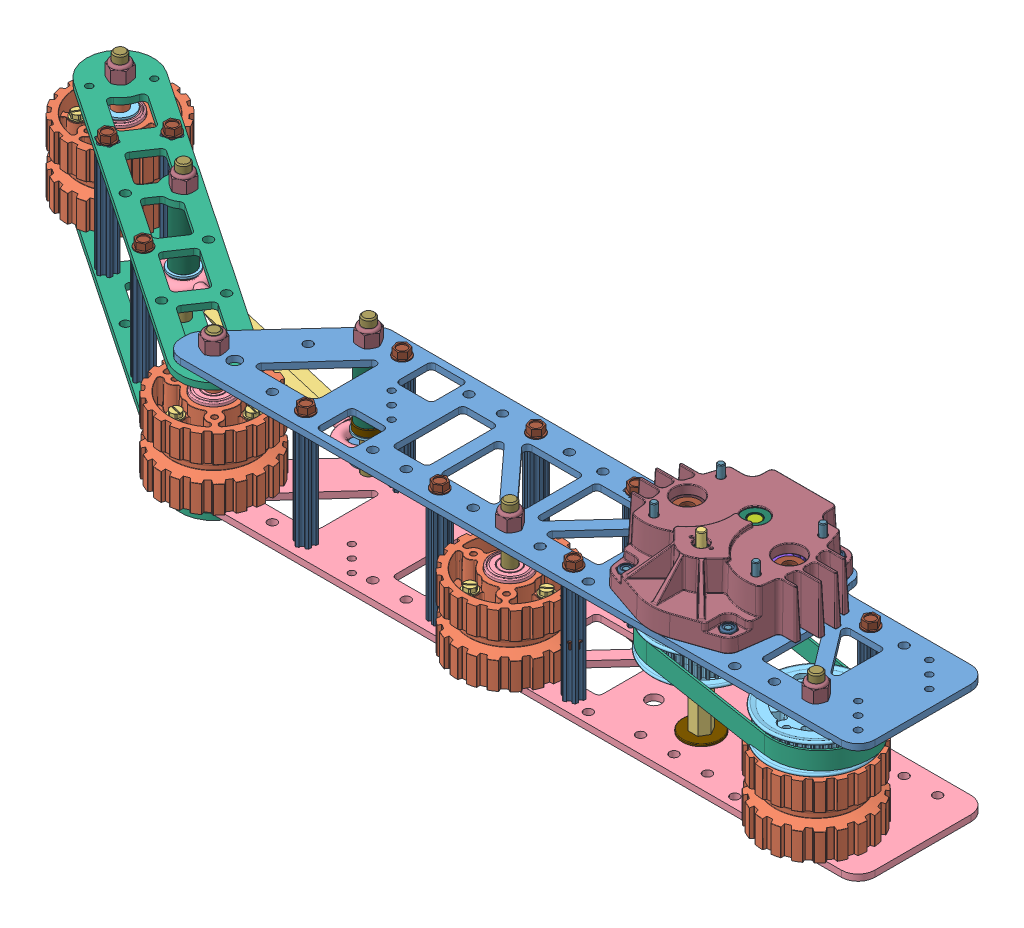
SolidWorks assembly TankDriveRightSide, configuration Default. Lengths in mm.
Overall size (781.55 148.41 261.62).
162 component instances, 41 part files, 0 mates.
Components (placement in the parent):
- am-3319 Inside Plate-1: am-3319 Inside Plate [Default] at (-236.8957 -8.1516 48.6059) size (527.05 4.76 117.47)
- 20T pulley back to back-1: 20T pulley back to back [Default] at (-148.1587 -69.0627 26.6681) x (0.970425 0 0.241402) z (-0.241402 0 0.970425) size (79.28 58.42 79.28)
  - am-3298 20 tooth Molded Tank Pulley Half r3-1: am-3298 20 tooth Molded Tank Pulley Half r3 [Default] at (-66.929 10.7589 19.6249) size (79.28 27.95 79.28)
  - am-3298 20 tooth Molded Tank Pulley Half r3-2: am-3298 20 tooth Molded Tank Pulley Half r3 [Default] at (-66.929 10.7589 19.6249) x (1 0 0) z (0 0 -1) size (79.28 27.95 79.28)
  - 10-24 Hex Washer Rolling x 1.25_93882A213-1: 10-24 Hex Washer Rolling x 1.25_93882A213 [Default] at (-46.3067 30.1899 7.7187) x (1 0 0) z (0 1 0) size (10.52 10.52 35.59)
  - 10-24 Hex Washer Rolling x 1.25_93882A213-2: 10-24 Hex Washer Rolling x 1.25_93882A213 [Default] at (-87.5512 30.1899 7.7187) x (1 0 0) z (0 1 0) size (10.52 10.52 35.59)
  - 10-24 Hex Washer Rolling x 1.25_93882A213-3: 10-24 Hex Washer Rolling x 1.25_93882A213 [Default] at (-66.929 30.1899 43.4374) x (1 0 0) z (0 1 0) size (10.52 10.52 35.59)
  - 10-24 Hex Washer Rolling x 1.25_93882A213-4: 10-24 Hex Washer Rolling x 1.25_93882A213 [Default] at (-66.929 -8.6721 -4.1876) x (-0.837169 0 -0.546944) z (0 -1 0) size (10.52 10.52 35.59)
  - 10-24 Hex Washer Rolling x 1.25_93882A213-5: 10-24 Hex Washer Rolling x 1.25_93882A213 [Default] at (-87.5512 -8.6721 31.5312) x (-0.837169 0 -0.546944) z (0 -1 0) size (10.52 10.52 35.59)
  - 10-24 Hex Washer Rolling x 1.25_93882A213-6: 10-24 Hex Washer Rolling x 1.25_93882A213 [Default] at (-46.3067 -8.6721 31.5312) x (-0.837169 0 -0.546944) z (0 -1 0) size (10.52 10.52 35.59)
  - 1614Z Bearing-1: 1614Z Bearing [Default] at (-66.929 -13.6886 19.6249) x (1 0 0) z (0 1 0) size (28.58 28.58 9.53)
  - 1614Z Bearing-2: 1614Z Bearing [Default] at (-66.929 35.2064 19.6249) x (1 0 0) z (0 -1 0) size (28.58 28.58 9.53)
- am-1393 375 washer-1: am-1393 375 washer [Default] at (-217.8457 -89.1141 29.5567) x (-0.876798 0 0.480859) z (-0.480859 0 -0.876798) size (20.62 1.6 20.62)
- am-3320 Upper Bar-1: am-3320 Upper Bar [Default] at (-436.3184 -98.6391 -117.8038) x (0.82904 0 0.55919) z (-0.55919 0 0.82904) size (314.32 4.76 50.8)
- am-3320 Upper Bar-2: am-3320 Upper Bar [Default] at (-436.3184 -12.9141 -117.8038) x (0.82904 0 0.55919) z (-0.55919 0 0.82904) size (314.32 4.76 50.8)
- 20T pulley back to back-2: 20T pulley back to back [Default] at (-417.8497 -69.0627 -185.0609) x (0.525428 0 -0.850838) z (0.850838 0 0.525428) size (79.28 58.42 79.28)
  - am-3298 20 tooth Molded Tank Pulley Half r3-1: am-3298 20 tooth Molded Tank Pulley Half r3 [Default] at (-66.929 10.7589 19.6249) size (79.28 27.95 79.28)
  - am-3298 20 tooth Molded Tank Pulley Half r3-2: am-3298 20 tooth Molded Tank Pulley Half r3 [Default] at (-66.929 10.7589 19.6249) x (1 0 0) z (0 0 -1) size (79.28 27.95 79.28)
  - 10-24 Hex Washer Rolling x 1.25_93882A213-1: 10-24 Hex Washer Rolling x 1.25_93882A213 [Default] at (-46.3067 30.1899 7.7187) x (1 0 0) z (0 1 0) size (10.52 10.52 35.59)
  - 10-24 Hex Washer Rolling x 1.25_93882A213-2: 10-24 Hex Washer Rolling x 1.25_93882A213 [Default] at (-87.5512 30.1899 7.7187) x (1 0 0) z (0 1 0) size (10.52 10.52 35.59)
  - 10-24 Hex Washer Rolling x 1.25_93882A213-3: 10-24 Hex Washer Rolling x 1.25_93882A213 [Default] at (-66.929 30.1899 43.4374) x (1 0 0) z (0 1 0) size (10.52 10.52 35.59)
  - 10-24 Hex Washer Rolling x 1.25_93882A213-4: 10-24 Hex Washer Rolling x 1.25_93882A213 [Default] at (-66.929 -8.6721 -4.1876) x (-0.837169 0 -0.546944) z (0 -1 0) size (10.52 10.52 35.59)
  - 10-24 Hex Washer Rolling x 1.25_93882A213-5: 10-24 Hex Washer Rolling x 1.25_93882A213 [Default] at (-87.5512 -8.6721 31.5312) x (-0.837169 0 -0.546944) z (0 -1 0) size (10.52 10.52 35.59)
  - 10-24 Hex Washer Rolling x 1.25_93882A213-6: 10-24 Hex Washer Rolling x 1.25_93882A213 [Default] at (-46.3067 -8.6721 31.5312) x (-0.837169 0 -0.546944) z (0 -1 0) size (10.52 10.52 35.59)
  - 1614Z Bearing-1: 1614Z Bearing [Default] at (-66.929 -13.6886 19.6249) x (1 0 0) z (0 1 0) size (28.58 28.58 9.53)
  - 1614Z Bearing-2: 1614Z Bearing [Default] at (-66.929 35.2064 19.6249) x (1 0 0) z (0 -1 0) size (28.58 28.58 9.53)
- Track Belt-1: Track Belt [Default] at (269.5297 -83.7039 93.0549) x (1 0 -0.000004) z (0.000004 0 1) (suppressed, hidden)
- am-2598_107 2016 KOP Toughbox Mini-1: am-2598_107 2016 KOP Toughbox Mini [Default] at (41.9977 -53.9307 20.5759) x (-0.999999 0 -0.001296) z (0 -1 0) size (140.05 121.81 142.29)
  - Toughbox d07-1: Toughbox d07 [Default] at (-88.5589 93.4503 -52.3959) x (-0.336928 0.94153 0) z (0.94153 0.336928 0) size (11 38.23 9.52)
  - Toughbox d05-1: Toughbox d05 [Default] at (-91.0349 50.9043 -67.5597) x (-0.336928 0.94153 0) z (0 0 -1) size (65.97 66.04 10.34)
  - FR6ZZ Bearing-1: FR6ZZ Bearing [Default] at (-96.247 60.278 -52.5991) x (-0.893862 0.448342 0) z (0 0 1) size (24.69 24.69 7.16)
  - 10-32 Nylock Nut-1: 10-32 Nylock Nut [Default] at (-129.8464 -8.0737 -56.3837) x (0.501678 0.865055 0) z (0 0 -1) size (9.53 11 5.96)
  - 10-32 Nylock Nut-2: 10-32 Nylock Nut [Default] at (-59.2462 80.7349 -56.3837) x (0.999999 -0.001296 0) z (0 0 -1) size (9.53 11 5.96)
  - 10-32 Nylock Nut-3: 10-32 Nylock Nut [Default] at (-122.7461 80.8172 -56.3837) x (0.500567 0.865698 0) z (0 0 -1) size (9.53 11 5.96)
  - 10-32 Nylock Nut-4: 10-32 Nylock Nut [Default] at (-52.3764 -8.1741 -56.3837) x (-0.501678 -0.865055 0) z (0 0 -1) size (9.53 11 5.96)
  - 5-16 washer-1: 5-16 washer [Default] at (-52.3162 38.3079 -77.7705) x (0.38418 -0.923258 0) z (0 0 -1) size (17.53 17.53 1.47)
  - 5-16 washer-2: 5-16 washer [Default] at (-52.3162 38.3079 -76.2973) x (0.897267 -0.441488 0) z (0 0 -1) size (17.53 17.53 1.47)
  - 5-16 washer-3: 5-16 washer [Default] at (-129.7861 38.4083 -77.7705) x (-0.990116 0.140253 0) z (0 0 1) size (17.53 17.53 1.47)
  - 5-16 washer-4: 5-16 washer [Default] at (-129.7861 38.4083 -79.2437) x (-0.681761 0.731575 0) z (0 0 1) size (17.53 17.53 1.47)
  - Toughbox d09-1: Toughbox d09 [Default] at (-52.3162 38.3079 -63.5973) x (0.910249 -0.414061 0) z (0 0 -1) size (20.03 20.32 12.7)
  - Toughbox d09-2: Toughbox d09 [Default] at (-129.7861 38.4083 -63.5973) x (0.075368 -0.997156 0) z (0 0 -1) size (20.03 20.32 12.7)
  - TM Housing-1: TM Housing [Default] at (-91.0876 10.1882 -86.3557) x (0.999999 -0.001296 0) z (0 0 1) size (139.9 118.55 41.62)
  - SHCS 10-32 x 0.625-1: SHCS 10-32 x 0.625 [Default] at (-52.2832 63.7078 -74.4685) x (-0.564778 -0.825243 0) z (-0.825243 0.564778 0) size (7.82 20.65 7.82)
  - SHCS 10-32 x 0.625-2: SHCS 10-32 x 0.625 [Default] at (-52.3491 12.9079 -74.4685) x (-0.564778 -0.825243 0) z (-0.825243 0.564778 0) size (7.82 20.65 7.82)
  - SHCS 10-32 x 0.625-3: SHCS 10-32 x 0.625 [Default] at (-129.7532 63.8083 -74.4685) x (-0.966277 -0.257503 0) z (-0.257503 0.966277 0) size (7.82 20.65 7.82)
  - SHCS 10-32 x 0.625-4: SHCS 10-32 x 0.625 [Default] at (-129.819 13.0083 -74.4685) x (-0.99652 0.083357 0) z (0.083357 0.99652 0) size (7.82 20.65 7.82)
  - R6ZZ Bearing-1: R6ZZ Bearing [Default] at (-91.0349 50.9043 -84.8317) x (0.958138 -0.286306 0) z (0 0 1) size (22.23 22.23 7.11)
  - R6ZZ Bearing-2: R6ZZ Bearing [Default] at (-91.0876 10.1882 -84.8317) x (-0.328282 -0.94458 0) z (0 0 1) size (22.23 22.23 7.11)
  - 8mm spring clip-1: 8mm spring clip [Default] at (-129.7861 38.4083 -63.5973) x (0 0 1) z (-1 0 0) size (1.12 14.83 14.83)
  - 8mm spring clip-2: 8mm spring clip [Default] at (-52.3162 38.3079 -63.5973) x (0 0 1) z (-1 0 0) size (1.12 14.83 14.83)
  - 500 E-klip-1: 500 E-klip [Default] at (-91.0876 10.1882 -64.4355) x (0.996411 -0.084651 0) z (0 0 1) size (19.07 20.96 1.27)
  - FR8ZZ Hex Bearing-1: FR8ZZ Hex Bearing [Default] at (-91.0876 10.1882 -44.6717) x (-0.5 0.866025 0) z (0 0 -1) size (31.12 31.12 7.93)
  - 16t 20dp 375h with teeth-1: 16t 20dp 375h with teeth [Default] at (-91.0349 50.9043 -67.5597) x (0 0 1) z (-0.983853 0.178977 0) size (15.19 22.57 22.57)
  - 48t 20dp 500h with teeth-1: 48t 20dp 500h with teeth [Default] at (-91.0876 10.1882 -63.1655) x (0 0 1) z (-1 0 0) size (10.21 63.42 63.42)
  - TB Output Shaft Hex L-Base 2-1: TB Output Shaft Hex L-Base 2 [Default] at (-52.7805 -6.4809 -52.3197) x (1 0 0) z (0 -1 0) size (14.66 142.29 12.7)
- am-3318 Outside Plate-1: am-3318 Outside Plate [Default] at (-236.8957 -93.8766 48.6068) x (1 0 -0.000004) z (0.000004 0 1) size (527.05 4.76 98.42)
- 20T pulley back to back-3: 20T pulley back to back [Default] at (305.2111 -69.0627 6.5885) x (0.998734 0 -0.050312) z (0.050312 0 0.998734) size (79.28 58.42 79.28)
  - am-3298 20 tooth Molded Tank Pulley Half r3-1: am-3298 20 tooth Molded Tank Pulley Half r3 [Default] at (-66.929 10.7589 19.6249) size (79.28 27.95 79.28)
  - am-3298 20 tooth Molded Tank Pulley Half r3-2: am-3298 20 tooth Molded Tank Pulley Half r3 [Default] at (-66.929 10.7589 19.6249) x (1 0 0) z (0 0 -1) size (79.28 27.95 79.28)
  - 10-24 Hex Washer Rolling x 1.25_93882A213-1: 10-24 Hex Washer Rolling x 1.25_93882A213 [Default] at (-46.3067 30.1899 7.7187) x (1 0 0) z (0 1 0) size (10.52 10.52 35.59)
  - 10-24 Hex Washer Rolling x 1.25_93882A213-2: 10-24 Hex Washer Rolling x 1.25_93882A213 [Default] at (-87.5512 30.1899 7.7187) x (1 0 0) z (0 1 0) size (10.52 10.52 35.59)
  - 10-24 Hex Washer Rolling x 1.25_93882A213-3: 10-24 Hex Washer Rolling x 1.25_93882A213 [Default] at (-66.929 30.1899 43.4374) x (1 0 0) z (0 1 0) size (10.52 10.52 35.59)
  - 10-24 Hex Washer Rolling x 1.25_93882A213-4: 10-24 Hex Washer Rolling x 1.25_93882A213 [Default] at (-66.929 -8.6721 -4.1876) x (-0.837169 0 -0.546944) z (0 -1 0) size (10.52 10.52 35.59)
  - 10-24 Hex Washer Rolling x 1.25_93882A213-5: 10-24 Hex Washer Rolling x 1.25_93882A213 [Default] at (-87.5512 -8.6721 31.5312) x (-0.837169 0 -0.546944) z (0 -1 0) size (10.52 10.52 35.59)
  - 10-24 Hex Washer Rolling x 1.25_93882A213-6: 10-24 Hex Washer Rolling x 1.25_93882A213 [Default] at (-46.3067 -8.6721 31.5312) x (-0.837169 0 -0.546944) z (0 -1 0) size (10.52 10.52 35.59)
  - 1614Z Bearing-1: 1614Z Bearing [Default] at (-66.929 -13.6886 19.6249) x (1 0 0) z (0 1 0) size (28.58 28.58 9.53)
  - 1614Z Bearing-2: 1614Z Bearing [Default] at (-66.929 35.2064 19.6249) x (1 0 0) z (0 -1 0) size (28.58 28.58 9.53)
- 20T pulley back to back-4: 20T pulley back to back [Default] at (-27.303 -69.0627 91.8147) x (-0.759399 0 0.650626) z (-0.650626 0 -0.759399) size (79.28 58.42 79.28)
  - am-3298 20 tooth Molded Tank Pulley Half r3-1: am-3298 20 tooth Molded Tank Pulley Half r3 [Default] at (-66.929 10.7589 19.6249) size (79.28 27.95 79.28)
  - am-3298 20 tooth Molded Tank Pulley Half r3-2: am-3298 20 tooth Molded Tank Pulley Half r3 [Default] at (-66.929 10.7589 19.6249) x (1 0 0) z (0 0 -1) size (79.28 27.95 79.28)
  - 10-24 Hex Washer Rolling x 1.25_93882A213-1: 10-24 Hex Washer Rolling x 1.25_93882A213 [Default] at (-46.3067 30.1899 7.7187) x (1 0 0) z (0 1 0) size (10.52 10.52 35.59)
  - 10-24 Hex Washer Rolling x 1.25_93882A213-2: 10-24 Hex Washer Rolling x 1.25_93882A213 [Default] at (-87.5512 30.1899 7.7187) x (1 0 0) z (0 1 0) size (10.52 10.52 35.59)
  - 10-24 Hex Washer Rolling x 1.25_93882A213-3: 10-24 Hex Washer Rolling x 1.25_93882A213 [Default] at (-66.929 30.1899 43.4374) x (1 0 0) z (0 1 0) size (10.52 10.52 35.59)
  - 10-24 Hex Washer Rolling x 1.25_93882A213-4: 10-24 Hex Washer Rolling x 1.25_93882A213 [Default] at (-66.929 -8.6721 -4.1876) x (-0.837169 0 -0.546944) z (0 -1 0) size (10.52 10.52 35.59)
  - 10-24 Hex Washer Rolling x 1.25_93882A213-5: 10-24 Hex Washer Rolling x 1.25_93882A213 [Default] at (-87.5512 -8.6721 31.5312) x (-0.837169 0 -0.546944) z (0 -1 0) size (10.52 10.52 35.59)
  - 10-24 Hex Washer Rolling x 1.25_93882A213-6: 10-24 Hex Washer Rolling x 1.25_93882A213 [Default] at (-46.3067 -8.6721 31.5312) x (-0.837169 0 -0.546944) z (0 -1 0) size (10.52 10.52 35.59)
  - 1614Z Bearing-1: 1614Z Bearing [Default] at (-66.929 -13.6886 19.6249) x (1 0 0) z (0 1 0) size (28.58 28.58 9.53)
  - 1614Z Bearing-2: 1614Z Bearing [Default] at (-66.929 35.2064 19.6249) x (1 0 0) z (0 -1 0) size (28.58 28.58 9.53)
- 42 - 2014 tooth pulley assembly-1: 42 - 2014 tooth pulley assembly [Default] at (239.3542 -10.8139 29.555) x (0 -1 0) z (0.542886 0 0.839807) size (23.46 74.23 74.23)
  - 42 tooth HTD Pulley half 2014-1: 42 tooth HTD Pulley half 2014 [Default] at origin size (13 74.23 74.23)
  - 42 tooth HTD Pulley half 2014-2: 42 tooth HTD Pulley half 2014 [Default] at (16.6624 0 0) x (-1 0 0) z (0 0.000084 1) size (13 74.23 74.23)
- FR8ZZ Hex Bearing-1: FR8ZZ Hex Bearing [Default] at (133.0984 -87.4732 10.5054) x (0.999999 0 0.001296) z (0 -1 0) size (31.12 31.12 7.93)
- 425-5M-15-1: 425-5M-15 [Default] at (133.0976 -29.6106 10.5059) x (0.987994 0 0.15449) z (-0.15449 0 0.987994) size (180.59 15 73.08)
- 500EX Hex Hub-1: 500EX Hex Hub [Default] at (133.0985 -9.259 10.5059) x (-0.999999 0 -0.001296) z (-0.001296 0 0.999999) size (55.37 25.4 51.33)
- 42 - 2014 tooth pulley assembly-2: 42 - 2014 tooth pulley assembly [Default] at (133.0976 -15.609 10.5059) x (0 -1 0) z (0.866683 0 -0.498859) size (23.46 74.23 74.23)
  - 42 tooth HTD Pulley half 2014-1: 42 tooth HTD Pulley half 2014 [Default] at origin size (13 74.23 74.23)
  - 42 tooth HTD Pulley half 2014-2: 42 tooth HTD Pulley half 2014 [Default] at (16.6624 0 0) x (-1 0 0) z (0 0.000084 1) size (13 74.23 74.23)
- BHCS 10-32 x 1000_SBHCSCREW 0.19-32x0.5-HX-C-1: BHCS 10-32 x 1000_SBHCSCREW 0.19-32x0.5-HX-C [Default] at (144.978 -9.7416 31.1435) x (0 -1 0) z (0.546944 0 -0.837169) size (28.48 9.29 9.24)
- BHCS 10-32 x 1000_SBHCSCREW 0.19-32x0.5-HX-C-2: BHCS 10-32 x 1000_SBHCSCREW 0.19-32x0.5-HX-C [Default] at (156.9109 -9.7416 10.5367) x (0 -1 0) z (0.546944 0 -0.837169) size (28.48 9.29 9.24)
- BHCS 10-32 x 1000_SBHCSCREW 0.19-32x0.5-HX-C-3: BHCS 10-32 x 1000_SBHCSCREW 0.19-32x0.5-HX-C [Default] at (145.0314 -9.7416 -10.1009) x (0 -1 0) z (0.546944 0 -0.837169) size (28.48 9.29 9.24)
- BHCS 10-32 x 1000_SBHCSCREW 0.19-32x0.5-HX-C-4: BHCS 10-32 x 1000_SBHCSCREW 0.19-32x0.5-HX-C [Default] at (121.1655 -9.7416 31.1126) x (0 -1 0) z (0.546944 0 -0.837169) size (28.48 9.29 9.24)
- BHCS 10-32 x 1000_SBHCSCREW 0.19-32x0.5-HX-C-5: BHCS 10-32 x 1000_SBHCSCREW 0.19-32x0.5-HX-C [Default] at (109.286 -9.7416 10.475) x (0 -1 0) z (0.546944 0 -0.837169) size (28.48 9.29 9.24)
- BHCS 10-32 x 1000_SBHCSCREW 0.19-32x0.5-HX-C-6: BHCS 10-32 x 1000_SBHCSCREW 0.19-32x0.5-HX-C [Default] at (121.219 -9.7416 -10.1318) x (0 -1 0) z (0.546944 0 -0.837169) size (28.48 9.29 9.24)
- 10-32 Nylock Nut-1: 10-32 Nylock Nut [Default] at (144.9784 -31.2554 31.1428) x (0.837169 0 0.546944) z (0 -1 0) size (9.53 11 5.96)
- 10-32 Nylock Nut-2: 10-32 Nylock Nut [Default] at (121.1659 -31.2554 31.1124) x (0.837169 0 0.546944) z (0 -1 0) size (9.53 11 5.96)
- 10-32 Nylock Nut-3: 10-32 Nylock Nut [Default] at (109.286 -31.2554 10.475) x (0.837169 0 0.546944) z (0 -1 0) size (9.53 11 5.96)
- 10-32 Nylock Nut-4: 10-32 Nylock Nut [Default] at (145.031 -31.2554 -10.1017) x (0.998579 0 0.053288) z (0 -1 0) size (9.53 11 5.96)
- 10-32 Nylock Nut-5: 10-32 Nylock Nut [Default] at (156.9109 -31.2554 10.5357) x (0.837169 0 0.546944) z (0 -1 0) size (9.53 11 5.96)
- 10-32 Nylock Nut-6: 10-32 Nylock Nut [Default] at (121.2185 -31.2554 -10.132) x (0.837169 0 0.546944) z (0 -1 0) size (9.53 11 5.96)
- 0985x0420 PVC Spacer-1: 0985x0420 PVC Spacer [Default] at (239.3542 -33.5516 29.555) x (-0.988623 0 0.150411) z (-0.150411 0 -0.988623) size (17.27 25.4 17.27)
- Churro-1: Churro [3.375in] at (-141.6457 -8.1516 -37.1191) x (0.744347 0 -0.667793) z (0 -1 0) size (14.66 12.7 85.72)
- Churro-2: Churro [3.375in] at (213.9543 -93.8766 -37.1191) x (-0.52346 0 0.85205) z (0 1 0) size (14.66 12.7 85.72)
- Churro-3: Churro [3.375in] at (-40.0457 -93.8766 35.9061) x (-0.324821 0 -0.945775) z (0 1 0) size (14.66 12.7 85.72)
- Churro-4: Churro [3.375in] at (-141.6457 -93.8766 35.9064) x (0.827953 0 0.560798) z (0 1 0) size (14.66 12.7 85.72)
- Churro-5: Churro [3.375in] at (61.5543 -93.8766 35.9057) x (-0.127351 0 0.991858) z (0 1 0) size (14.66 12.7 85.72)
- Churro-6: Churro [3.375in] at (36.154 -89.1141 -37.1192) x (-0.759985 0 0.649941) z (0 1 0) size (14.66 12.7 85.72)
- Churro-7: Churro [3.375in] at (-40.046 -8.1516 -37.1189) x (-0.660407 0 0.750908) z (0 -1 0) size (14.66 12.7 85.72)
- FHTS 0.25-20-0.75_FHTS 0.25-20-G-0.75-C-1: FHTS 0.25-20-0.75_FHTS 0.25-20-G-0.75-C [Default] at (213.9543 -93.8766 -37.1191) x (0 1 0) z (-0.996716 0 0.080972) size (24.64 12.19 12.19)
- FHTS 0.25-20-0.75_FHTS 0.25-20-G-0.75-C-2: FHTS 0.25-20-0.75_FHTS 0.25-20-G-0.75-C [Default] at (36.1543 -93.8766 -37.1191) x (0 1 0) z (-0.982775 0 -0.184807) size (24.64 12.19 12.19)
- FHTS 0.25-20-0.75_FHTS 0.25-20-G-0.75-C-3: FHTS 0.25-20-0.75_FHTS 0.25-20-G-0.75-C [Default] at (-141.6457 -93.8766 -37.1191) x (0 1 0) z (-0.844513 0 0.535535) size (24.64 12.19 12.19)
- FHTS 0.25-20-0.75_FHTS 0.25-20-G-0.75-C-4: FHTS 0.25-20-0.75_FHTS 0.25-20-G-0.75-C [Default] at (-141.6457 -93.8766 35.9059) x (0 1 0) z (-0.853192 0 0.521597) size (24.64 12.19 12.19)
- FHTS 0.25-20-0.75_FHTS 0.25-20-G-0.75-C-5: FHTS 0.25-20-0.75_FHTS 0.25-20-G-0.75-C [Default] at (-40.0457 -93.8766 35.9059) x (0 1 0) z (-0.544096 0 0.839023) size (24.64 12.19 12.19)
- FHTS 0.25-20-0.75_FHTS 0.25-20-G-0.75-C-6: FHTS 0.25-20-0.75_FHTS 0.25-20-G-0.75-C [Default] at (61.5543 -49.7177 35.9059) x (0 1 0) z (-0.654907 0 0.755709) size (24.64 12.19 12.19)
- FHTS 0.25-20-0.75_FHTS 0.25-20-G-0.75-C-7: FHTS 0.25-20-0.75_FHTS 0.25-20-G-0.75-C [Default] at (61.5543 -3.3891 35.9057) x (0 -1 0) z (0.841836 0 0.539733) size (24.64 12.19 12.19)
- FHTS 0.25-20-0.75_FHTS 0.25-20-G-0.75-C-8: FHTS 0.25-20-0.75_FHTS 0.25-20-G-0.75-C [Default] at (36.154 -3.3891 -37.1192) x (0 -1 0) z (0.90252 0 0.430648) size (24.64 12.19 12.19)
- FHTS 0.25-20-0.75_FHTS 0.25-20-G-0.75-C-9: FHTS 0.25-20-0.75_FHTS 0.25-20-G-0.75-C [Default] at (213.954 -3.3891 -37.1199) x (0 -1 0) z (0.505395 0 -0.862888) size (24.64 12.19 12.19)
- FHTS 0.25-20-0.75_FHTS 0.25-20-G-0.75-C-10: FHTS 0.25-20-0.75_FHTS 0.25-20-G-0.75-C [Default] at (-40.046 -3.3891 -37.1189) x (0 -1 0) z (-0.666202 0 0.745771) size (24.64 12.19 12.19)
- FHTS 0.25-20-0.75_FHTS 0.25-20-G-0.75-C-11: FHTS 0.25-20-0.75_FHTS 0.25-20-G-0.75-C [Default] at (-40.0457 -3.3891 35.9061) x (0 -1 0) z (-0.852203 0 0.523211) size (24.64 12.19 12.19)
- FHTS 0.25-20-0.75_FHTS 0.25-20-G-0.75-C-12: FHTS 0.25-20-0.75_FHTS 0.25-20-G-0.75-C [Default] at (-141.6457 -3.3891 35.9064) x (0 -1 0) z (-0.822487 0 -0.568784) size (24.64 12.19 12.19)
- FHTS 0.25-20-0.75_FHTS 0.25-20-G-0.75-C-13: FHTS 0.25-20-0.75_FHTS 0.25-20-G-0.75-C [Default] at (-141.646 -3.3891 -37.1186) x (0 -1 0) z (0.317681 0 0.948198) size (24.64 12.19 12.19)
- FHTS 0.25-20-0.75_FHTS 0.25-20-G-0.75-C-14: FHTS 0.25-20-0.75_FHTS 0.25-20-G-0.75-C [Default] at (-40.0457 -93.8766 -37.1191) x (0 1 0) z (0.471275 0 0.881986) size (24.64 12.19 12.19)
- 375-16 x 4.25 Hex Bolt_HFBOLT 0.375-16x2.5x1-C-1: 375-16 x 4.25 Hex Bolt_HFBOLT 0.375-16x2.5x1-C [Default] at (239.3543 -100.0488 29.555) x (0 1 0) z (0.360898 0 -0.932605) size (114.12 16.48 14.28)
- 375-16 x 4.25 Hex Bolt_HFBOLT 0.375-16x2.5x1-C-2: 375-16 x 4.25 Hex Bolt_HFBOLT 0.375-16x2.5x1-C [Default] at (10.7543 -100.0488 33.3659) x (0 1 0) z (0.795097 0 -0.606483) size (114.12 16.48 14.28)
- 3-8-16 NyLock Nut - Mcm 95615A140_95615A140-1: 3-8-16 NyLock Nut - Mcm 95615A140_95615A140 [Default] at (239.3543 -3.3891 29.555) x (0.904574 0 0.426316) z (-0.426316 0 0.904574) size (14.29 12 16.5)
- 3-8-16 NyLock Nut - Mcm 95615A140_95615A140-2: 3-8-16 NyLock Nut - Mcm 95615A140_95615A140 [Default] at (10.7543 -3.3891 33.3659) x (0.894806 0 0.446455) z (-0.446455 0 0.894806) size (14.29 12 16.5)
- 3-8-16 NyLock Nut - Mcm 95615A140_95615A140-3: 3-8-16 NyLock Nut - Mcm 95615A140_95615A140 [Default] at (-436.3184 -8.1516 -117.8038) x (-0.991923 0 0.12684) z (-0.12684 0 -0.991923) size (14.29 12 16.5)
- 10-32x0625_shcs_HX-SHCS 0.19-32x1.375x1-C-1: 10-32x0625_shcs_HX-SHCS 0.19-32x1.375x1-C [Default] at (94.4397 -12.9776 28.8193) x (0 1 0) z (0.347631 0 -0.937631) size (20.7 7.94 7.94)
- 10-32x0625_shcs_HX-SHCS 0.19-32x1.375x1-C-2: 10-32x0625_shcs_HX-SHCS 0.19-32x1.375x1-C [Default] at (171.7573 -12.9776 28.8193) x (0 1 0) z (0.46908 0 -0.883156) size (20.7 7.94 7.94)
- 10-32x0625_shcs_HX-SHCS 0.19-32x1.375x1-C-3: 10-32x0625_shcs_HX-SHCS 0.19-32x1.375x1-C [Default] at (164.8485 -12.9776 -60.0553) x (0 1 0) z (0.850684 0 -0.525677) size (20.7 7.94 7.94)
- 10-32x0625_shcs_HX-SHCS 0.19-32x1.375x1-C-4: 10-32x0625_shcs_HX-SHCS 0.19-32x1.375x1-C [Default] at (101.3485 -12.9776 -60.0553) x (0 1 0) z (0.126293 0 -0.991993) size (20.7 7.94 7.94)
- FHTS 0.25-20-0.75_FHTS 0.25-20-G-0.75-C-15: FHTS 0.25-20-0.75_FHTS 0.25-20-G-0.75-C [Default] at (-400.1973 -8.1516 -71.9935) x (0 -1 0) z (-0.838639 0 0.544688) size (24.64 12.19 12.19)
- FHTS 0.25-20-0.75_FHTS 0.25-20-G-0.75-C-16: FHTS 0.25-20-0.75_FHTS 0.25-20-G-0.75-C [Default] at (-315.9669 -8.1516 -15.1798) x (0 -1 0) z (-0.073627 0 0.997286) size (24.64 12.19 12.19)
- am-1393 375 washer-2: am-1393 375 washer [Default] at (-436.3178 -29.0939 -117.8054) size (20.62 1.6 20.62)
- 375-16 x 4.25 Hex Bolt_HFBOLT 0.375-16x2.5x1-C-3: 375-16 x 4.25 Hex Bolt_HFBOLT 0.375-16x2.5x1-C [Default] at (-163.871 -100.0488 -33.9435) x (0 1 0) z (0.84094 0 -0.541129) size (114.12 16.48 14.28)
- 3-8-16 NyLock Nut - Mcm 95615A140_95615A140-4: 3-8-16 NyLock Nut - Mcm 95615A140_95615A140 [Default] at (-163.8707 -3.3891 -33.9441) x (0.866025 0 -0.5) z (0.5 0 0.866025) size (14.29 12 16.5)
- 3-8-16 NyLock Nut - Mcm 95615A140_95615A140-5: 3-8-16 NyLock Nut - Mcm 95615A140_95615A140 [Default] at (-340.3278 -8.1516 -69.9086) x (0.55919 0 -0.82904) z (0.82904 0 0.55919) size (14.29 12 16.5)
- 375-16 x 4.25 Hex Bolt_HFBOLT 0.375-16x2.5x1-C-4: 375-16 x 4.25 Hex Bolt_HFBOLT 0.375-16x2.5x1-C [Default] at (-340.3278 -104.8113 -69.9086) x (0 1 0) z (0.999997 0 -0.002563) size (114.12 16.48 14.28)
- am-0243 spacer 1860x0420-1: am-0243 spacer 1860x0420 [Default] at (-163.8706 -8.1516 -33.9446) x (0.842912 0 -0.538051) z (0 -1 0) size (17.27 17.27 47.24)
- am-0243 spacer 1860x0420-2: am-0243 spacer 1860x0420 [Default] at (-340.3278 -60.1581 -69.9086) x (0.260138 0 0.965571) z (0 1 0) size (17.27 17.27 47.24)
- 500 Hex Collar Clamp-1: 500 Hex Collar Clamp [Default] at (67.8484 -3.0504 0.9895) x (-0.999999 0 -0.001296) z (-0.001296 0 0.999999) size (32.26 10.41 31.75)
  - Hex Collar 500-1: Hex Collar 500 [Default] at (-65.2624 31.6086 9.4318) size (31.73 10.41 31.75)
  - 8-32 x 0375 SHCS-1: 8-32 x 0375 SHCS [Default] at (-53.7269 36.8156 13.4323) x (0 0 -1) z (0.687397 0.726282 0) size (13.71 6.86 6.86)
- Churro-8: Churro [3.375in] at (-400.1973 -8.1516 -71.9935) x (0.898792 0 -0.438375) z (0 -1 0) size (14.66 12.7 85.72)
- Churro-9: Churro [3.375in] at (-315.9669 -98.6391 -15.1798) x (0.82904 0 0.55919) z (0 1 0) size (14.66 12.7 85.72)
- 375-16 x 4.25 Hex Bolt_HFBOLT 0.375-16x2.5x1-C-5: 375-16 x 4.25 Hex Bolt_HFBOLT 0.375-16x2.5x1-C [Default] at (-217.8457 -104.8113 29.5567) x (0 1 0) z (-0.999842 0 -0.017748) size (114.12 16.48 14.28)
- 3-8-16 NyLock Nut - Mcm 95615A140_95615A140-6: 3-8-16 NyLock Nut - Mcm 95615A140_95615A140 [Default] at (-217.8457 -3.3891 29.5567) x (-0.358027 0 0.933711) z (-0.933711 0 -0.358027) size (14.29 12 16.5)
- Spacer am-1181-1: Spacer am-1181 [Default] at (-163.871 -60.1708 -33.9435) x (-0.99086 0 0.134894) z (0 -1 0) size (19.05 19.05 4.78)
- Round Collar 375-1: Round Collar 375 [Default] at (-340.3278 -80.5359 -69.9086) x (0.531625 0 0.84698) z (-0.84698 0 0.531625) size (22.2 9.53 22.23)
- am-2243 brass spacer-1: am-2243 brass spacer [Default] at (-436.3184 -25.8225 -117.8038) x (1 0 0) z (0 1 0) size (11.1 11.1 20.83)
- am-2243 brass spacer-2: am-2243 brass spacer [Default] at (-217.8457 -16.1855 29.5567) x (0.997568 0 0.069694) z (0 -1 0) size (11.1 11.1 20.83)
- am-1393 375 washer-3: am-1393 375 washer [Default] at (-163.871 -61.771 -33.9435) size (20.62 1.6 20.62)
- am-1393 375 washer-4: am-1393 375 washer [Default] at (-340.3278 -60.1581 -69.9086) x (-0.759241 0 -0.65081) z (-0.65081 0 0.759241) size (20.62 1.6 20.62)
- am-3321 turnbuckle-1: am-3321 turnbuckle [Default] at (-104.1591 -141.7961 136.3618) x (0.974371 0 0.224947) z (0.224947 0 -0.974371) size (215.9 15.75 34.92)
  - Turnbuckle Body-1: Turnbuckle Body [Default] at (-241.5909 -75.2753 147.8583) size (111.12 15.75 18.18)
  - Turnbuckle Rod-1: Turnbuckle Rod [Default] at (-200.3159 -75.2753 147.8583) x (-1 0 0) z (0 0 -1) size (93.66 9.78 34.92)
  - Turnbuckle Rod-2: Turnbuckle Rod [Default] at (-171.7409 -75.2753 147.8583) size (93.66 9.78 34.92)
- Churro-10: Churro [3.375in] at (-380.3125 -93.8766 -101.4741) x (-0.32865 0 0.944452) z (0 1 0) size (14.66 12.7 85.72)
- FHTS 0.25-20-0.75_FHTS 0.25-20-G-0.75-C-17: FHTS 0.25-20-0.75_FHTS 0.25-20-G-0.75-C [Default] at (-380.3125 -8.1516 -101.4741) x (0 -1 0) z (0.893117 0 -0.449825) size (24.64 12.19 12.19)
- FHTS 0.25-20-0.75_FHTS 0.25-20-G-0.75-C-18: FHTS 0.25-20-0.75_FHTS 0.25-20-G-0.75-C [Default] at (-380.3125 -98.6391 -101.4741) x (0 1 0) z (0.146532 0 -0.989206) size (24.64 12.19 12.19)
- Round Collar 375-2: Round Collar 375 [Default] at (-163.8706 -80.5359 -33.9446) size (22.2 9.53 22.23)
- FHTS 0.25-20-0.75_FHTS 0.25-20-G-0.75-C-19: FHTS 0.25-20-0.75_FHTS 0.25-20-G-0.75-C [Default] at (-315.9669 -98.6391 -15.1798) x (0 1 0) z (-0.100553 0 -0.994932) size (24.64 12.19 12.19)
- 375-16 x 4.25 Hex Bolt_HFBOLT 0.375-16x2.5x1-C-6: 375-16 x 4.25 Hex Bolt_HFBOLT 0.375-16x2.5x1-C [Default] at (-436.3184 -104.8113 -117.8038) x (0 1 0) z (0.999997 0 -0.002563) size (114.12 16.48 14.28)
